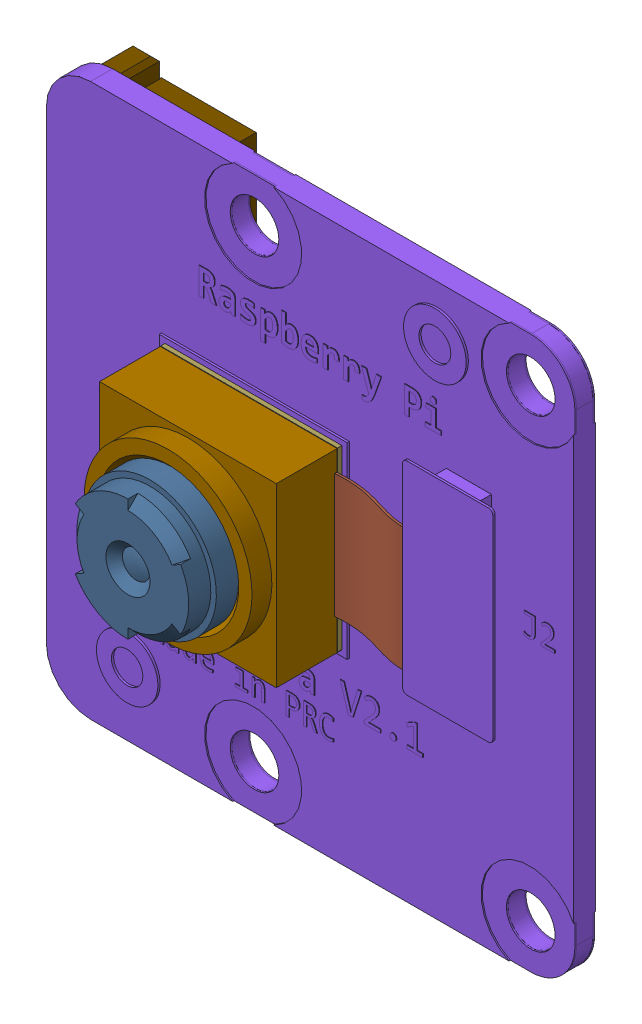
SolidWorks assembly RspCameraMia, configuration Default. Lengths in mm.
Overall size (23.86 25 9.96).
41 component instances, 22 part files, 0 mates.
Components (placement in the parent):
- RspCameraMia.stp-1: RspCameraMia.stp [Default] at origin size (23.86 25 9.96)
  - 70521906.stp-1: 70521906.stp [Default] at (1.7167 0.8597 0.0159) size (2 2.1 0.95)
    - 70521906_01.stp-1: 70521906_01.stp [Default] at origin size (0.25 0.55 0.75)
    - 70521906_02.stp-1: 70521906_02.stp [Default] at origin size (0.25 0.55 0.75)
    - 70521906_03.stp-1: 70521906_03.stp [Default] at origin size (2 1.25 0.9)
    - 70521906_04.stp-1: 70521906_04.stp [Default] at origin size (0.25 0.55 0.75)
    - 70521906_05.stp-1: 70521906_05.stp [Default] at origin size (0.25 0.55 0.75)
    - 70521906_06.stp-1: 70521906_06.stp [Default] at origin size (0.25 0.55 0.75)
    - 70521906_07.stp-1: 70521906_07.stp [Default] at origin size (0.25 0.55 0.75)
  - PicameraPCB.stp-1: PicameraPCB.stp [Default] at (0.2393 -0.0199 0) x (-1 0 0) z (0 0 1) size (23.86 25 2.2)
  - OVA5647_Housing.stp-1: OVA5647_Housing.stp [Default] at (-2.4078 0.0859 1) x (1 0 0) z (0 -1 0) size (8 3.95 8)
  - OVA5647_Lens_FOV.stp-1: OVA5647_Lens_FOV.stp [Default] at (-2.4087 0.0921 5.963) x (1 0 0) z (0 -1 0) size (6 3.35 6)
  - ribbon_cam.stp-1: ribbon_cam.stp [Default] at (-2.4804 0.3633 1.4162) x (0 1 0) z (1 0 0) size (5.6 0.69 4.76)
  - CCD.stp-1: CCD.stp [Default] at (-2.0757 0.287 1.296) x (1 0 0) z (0 -1 0) size (8.01 0.69 8.01)
  - CAPC-0805-T0.75-BN.stp-1: CAPC-0805-T0.75-BN.stp [Default] at (4.562 5.9833 -0.0026) x (0 -1 0) z (0 0 -1) size (2.1 1.35 0.75)
  - CAPC-0805-T0.75-BN.stp-2: CAPC-0805-T0.75-BN.stp [Default] at (2.0233 10.2705 -0.0026) x (0 -1 0) z (0 0 -1) size (2.1 1.35 0.75)
  - CAPC-0402-T0.55-BN.stp-1: CAPC-0402-T0.55-BN.stp [Default] at (-2.9562 6.224 -0.2572) x (-1 0 0) z (0 -1 0) size (1.05 0.55 0.55)
  - CAPC-0402-T0.55-BN.stp-2: CAPC-0402-T0.55-BN.stp [Default] at (-2.9504 5.2898 -0.2691) x (-1 0 0) z (0 -1 0) size (1.05 0.55 0.55)
  - CAPC-0402-T0.55-BN.stp-3: CAPC-0402-T0.55-BN.stp [Default] at (4.5768 -5.1833 -0.2811) x (-1 0 0) z (0 -1 0) size (1.05 0.55 0.55)
  - CAPC-0402-T0.55-BN.stp-4: CAPC-0402-T0.55-BN.stp [Default] at (2.5547 -5.1368 -0.2811) x (-1 0 0) z (0 -1 0) size (1.05 0.55 0.55)
  - CAPC-0402-T0.55-BN.stp-5: CAPC-0402-T0.55-BN.stp [Default] at (2.6129 -9.93 -0.293) x (-1 0 0) z (0 -1 0) size (1.05 0.55 0.55)
  - CAPC-0402-T0.55-BN.stp-6: CAPC-0402-T0.55-BN.stp [Default] at (4.7286 -9.9294 -0.293) x (-1 0 0) z (0 -1 0) size (1.05 0.55 0.55)
  - CAPC-0402-T0.55-BN.stp-7: CAPC-0402-T0.55-BN.stp [Default] at (8.4068 -3.8793 -0.2811) x (-1 0 0) z (0 -1 0) size (1.05 0.55 0.55)
  - CAPC-0402-T0.55-BN.stp-8: CAPC-0402-T0.55-BN.stp [Default] at (9.0088 0.0217 -0.2796) x (0 1 0) z (-1 0 0) size (1.05 0.55 0.55)
  - CAPC-0402-T0.55-BN.stp-9: CAPC-0402-T0.55-BN.stp [Default] at (10.4284 2.6731 -0.3022) x (0 1 0) z (-1 0 0) size (1.05 0.55 0.55)
  - CAPC-0402-T0.55-BN.stp-10: CAPC-0402-T0.55-BN.stp [Default] at (8.2321 1.3259 -0.2838) x (1 0 0) z (0 1 0) size (1.05 0.55 0.55)
  - RESC-0402.stp-1: RESC-0402.stp [Default] at (3.7919 0.0148 -0.0114) x (1 0 0) z (0 0 -1) size (1.05 0.55 0.4)
  - RESC-0402.stp-2: RESC-0402.stp [Default] at (4.1232 2.6296 -0.0028) x (0 -1 0) z (0 0 -1) size (1.05 0.55 0.4)
  - RESC-0402.stp-3: RESC-0402.stp [Default] at (10.5883 -6.2795 -0.0019) x (0 1 0) z (0 0 -1) size (1.05 0.55 0.4)
  - RESC-0603.stp-1: RESC-0603.stp [Default] at (-2.6191 7.0617 -0.0121) x (1 0 0) z (0 0 -1) size (1.7 0.9 0.55)
  - RESC-0603.stp-2: RESC-0603.stp [Default] at (-3.4466 3.0018 -0.0048) x (0 -1 0) z (0 0 -1) size (1.7 0.9 0.55)
  - RESC-1210.stp-1: RESC-1210.stp [Default] at (2.2265 5.9002 -0.0068) x (0 -1 0) z (0 0 -1) size (3.3 2.7 0.6)
  - c-1-1734248-5-e-raspberry_display.stp-1: c-1-1734248-5-e-raspberry_display.stp [Default] at (-10.6651 0.0449 -1.5) x (0 -1 0) z (-1 0 0) size (22.4 3.22 5.68)
  - SOT23-5.stp-1: SOT23-5.stp [Default] at (4.2989 9.8879 0.5457) x (0 -1 0) z (0 0 -1) size (2.84 3.01 1.19)
  - SOT23-5.stp-2: SOT23-5.stp [Default] at (3.5194 -3.2493 0.04) x (-1 0 0) z (0 0 -1) size (2.84 3.01 1.19)
  - SOT23-5.stp-3: SOT23-5.stp [Default] at (3.5816 -8.055 0.0206) x (-1 0 0) z (0 0 -1) size (2.84 3.01 1.19)
  - KX7 SMD Quartz Crystal Resonator 3.2x2.5mm.stp-1: KX7 SMD Quartz Crystal Resonator 3.2x2.5mm.stp [Default] at (9.9746 -4.9221 0.0339) x (-1 0 0) z (0 -1 0) size (3.2 0.6 2.5)
  - c6aaa.stp-1: c6aaa.stp [Default] at (0.0643 0.0942 0) x (1 0 0) z (0 0 -1) size (2 2.99 0.6)
  - 4pin_smd.stp-1: 4pin_smd.stp [Default] at (0.027 0.0676 0) x (1 0 0) z (0 0 -1) size (1.29 1 0.47)
  - 4pin_smd.stp-2: 4pin_smd.stp [Default] at (-0.0093 -6.0092 -0.0198) x (1 0 0) z (0 0 -1) size (1.29 1 0.47)
  - 4pin_smd.stp-3: 4pin_smd.stp [Default] at (0.0326 -3.0068 -0.0235) x (1 0 0) z (0 0 -1) size (1.29 1 0.47)
